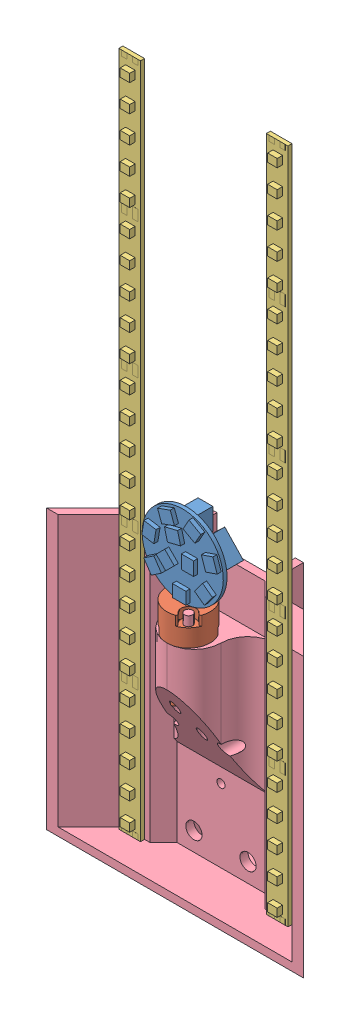
SolidWorks assembly Center-Decke, configuration Standard. Lengths in mm.
Overall size (95 253 47.31).
5 component instances, 4 part files, 12 mates.
Components (placement in the parent):
- G4 LED-1: G4 LED [Standard] at (-69.3938 71.9428 102.9201) x (-1 0 0) z (0 1 0) size (30 9.9 34.79)
- G4 Sockel-1: G4 Sockel [Standard] at (-69.3938 46.9428 102.1701) x (0.707107 0 0.707107) z (0 1 0) size (16 16 33.5)
- LED-Bar-1: LED-Bar [Standard] at (-38.1365 214.9428 95.1701) x (0 1 0) z (1 0 0) size (250 3.5 8)
- LED-Bar-2: LED-Bar [Standard] at (-92.6512 214.9428 95.1701) x (0 1 0) z (1 0 0) size (250 3.5 8)
- Center-Decke-Gehäuse-Left-1: Center-Decke-Gehäuse-Left [Standard] at (-69.3938 -38.0572 77.1701) size (95 103 44)
Mates (geometry in assembly coordinates):
- Deckungsgleich1: coincident anti-aligned: plane of LED-Bar-1 through (-38.1365 214.9428 95.1701) normal (0 0 -1); plane of Center-Decke-Gehäuse-Left-1 through (-48.1365 64.9428 95.1701) normal (0 0 1)
- Deckungsgleich2: coincident anti-aligned: plane of LED-Bar-2 through (-92.6512 214.9428 95.1701) normal (0 0 -1); plane of Center-Decke-Gehäuse-Left-1 through (-90.6512 64.9428 95.1701) normal (0 0 1)
- Deckungsgleich3: coincident anti-aligned: plane of LED-Bar-2 through (-92.6512 -35.0572 96.6701) normal (0 -1 0); plane of Center-Decke-Gehäuse-Left-1 through (-69.3938 -35.0572 77.1701) normal (0 1 0)
- Deckungsgleich4: coincident anti-aligned: plane of LED-Bar-1 through (-38.1365 -35.0572 96.6701) normal (0 -1 0); plane of Center-Decke-Gehäuse-Left-1 through (-69.3938 -35.0572 77.1701) normal (0 1 0)
- Deckungsgleich5: coincident anti-aligned: line of LED-Bar-1 through (-38.1365 -35.0572 95.1701) axis (0 1 0); line of Center-Decke-Gehäuse-Left-1 through (-38.1365 64.9428 95.1701) axis (0 -1 0)
- Deckungsgleich6: coincident aligned: line of LED-Bar-2 through (-100.6512 214.9428 95.1701) axis (0 -1 0); line of Center-Decke-Gehäuse-Left-1 through (-100.6512 64.9428 95.1701) axis (0 -1 0)
- Deckungsgleich7: coincident anti-aligned: plane of G4 Sockel-1 through (-69.3938 46.9428 102.1701) normal (0 -1 0); plane of Center-Decke-Gehäuse-Left-1 through (-79.3938 46.9428 110.1701) normal (0 1 0)
- Konzentrisch1: concentric anti-aligned: cylinder of G4 Sockel-1 through (-73.6365 46.9428 97.9274) axis (0 1 0) radius 1.5; cylinder of Center-Decke-Gehäuse-Left-1 through (-73.6365 56.9428 97.9274) axis (0 -1 0) radius 1.5
- Konzentrisch2: concentric anti-aligned: cylinder of G4 Sockel-1 through (-65.1512 46.9428 106.4127) axis (0 1 0) radius 1.5; cylinder of Center-Decke-Gehäuse-Left-1 through (-65.1512 56.9428 106.4127) axis (0 -1 0) radius 1.5
- Konzentrisch3: concentric anti-aligned: cylinder of G4 Sockel-1 through (-66.8938 46.9428 102.1701) axis (0 1 0) radius 0.75; cylinder of G4 LED-1 through (-66.8938 59.6577 102.1701) axis (0 -1 0) radius 0.75
- Konzentrisch4: concentric anti-aligned: cylinder of G4 LED-1 through (-71.8938 59.6577 102.1701) axis (0 -1 0) radius 0.75; cylinder of G4 Sockel-1 through (-71.8938 46.9428 102.1701) axis (0 1 0) radius 0.75
- Tangential2: tangent anti-aligned: cylinder of G4 LED-1 through (-69.3938 71.9428 104.3201) axis (0 0 -1) radius 15; plane of G4 Sockel-1 through (-69.3938 56.9428 102.1701) normal (0 1 0)
